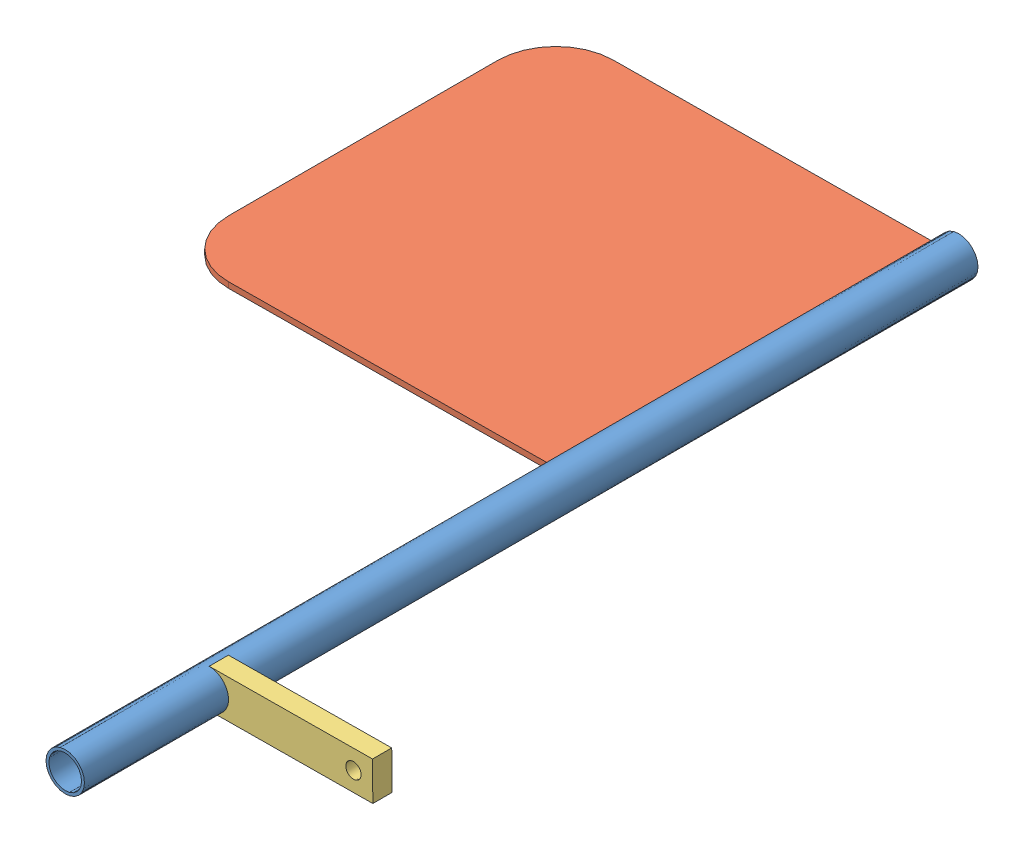
SolidWorks assembly Ensemble safran, configuration Défaut. Lengths in mm.
Overall size (295.07 20.7 465).
3 component instances, 3 part files, 6 mates.
Components (placement in the parent):
- Tube 20x1.5-1: Tube 20x1.5 [Défaut] at (-30.4914 -1.6375 -232.5) size (20 20 465)
- safran-1: safran [Défaut] at (-240.4827 -3.5629 -232.5) x (0.999966 0.008209 0) z (0.008209 -0.999966 0) size (200 200 3)
- biellette 20x10-1: biellette 20x10 [Défaut] at (-40.5732 8.2801 147.5) x (0.999966 0.008209 0) z (0 0 1) size (85 20 10)
Mates (geometry in assembly coordinates):
- Tangent1: tangent anti-aligned: cylinder of Tube 20x1.5-1 through (-30.4914 -1.6375 232.5) axis (0 0 -1) radius 10; plane of safran-1 through (-40.4648 -4.9211 -232.5) normal (0.999966 0.008209 0)
- Distance4: distance = 0.5 mm: line of safran-1 through (-40.4648 -4.9211 -232.5) axis (0 0 1); cylinder of Tube 20x1.5-1 through (-30.4914 -1.6375 232.5) axis (0 0 -1) radius 10
- Coïncidente6: coincident aligned: plane of Tube 20x1.5-1 through (-30.4914 -1.6375 -232.5) normal (0 0 -1); plane of safran-1 through (-210.4591 -6.3165 -232.5) normal (0 0 -1)
- Coaxiale1: concentric aligned: cylinder of Tube 20x1.5-1 through (-30.4914 -1.6375 232.5) axis (0 0 -1) radius 10; cylinder of biellette 20x10-1 through (-30.4914 -1.6375 157.5) axis (0 0 -1) radius 10
- Distance5: distance = 75 mm aligned: plane of Tube 20x1.5-1 through (-30.4914 -1.6375 232.5) normal (0 0 1); plane of biellette 20x10-1 through (-30.4914 -1.6375 157.5) normal (0 0 1)
- Parallèle3: parallel anti-aligned: line of safran-1 through (-40.4648 -4.9211 -32.5) axis (-0.999966 -0.008209 0); line of biellette 20x10-1 through (-30.4093 -11.6372 157.5) axis (0.999966 0.008209 0)
